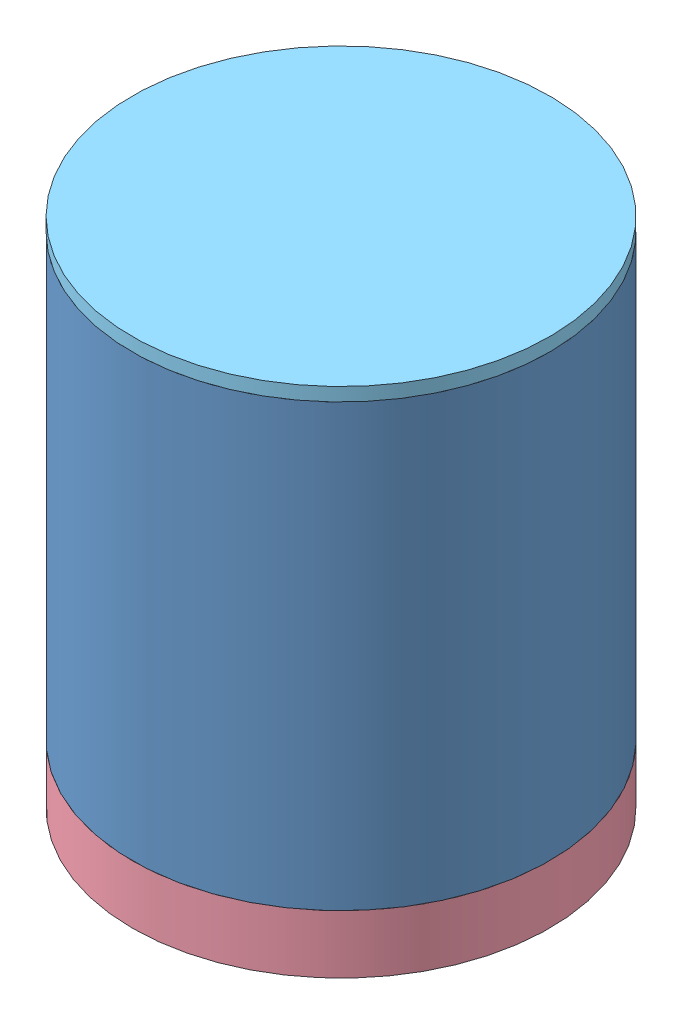
SolidWorks assembly Flour Dis. MEchanism_1.4, configuration Default. Lengths in mm.
Overall size (170.44 160 170.44).
5 component instances, 5 part files, 12 mates.
Components (placement in the parent):
- Flour container_ top part-1: Flour container_ top part [Default] at origin size (125 140 125)
- Flour Dis. MEchanism-2: Flour Dis. MEchanism [Default] at (0 -6 0) x (0.999465 0 -0.032695) z (0.032695 0 0.999465) size (118 10 118)
- Flour tracker-2: Flour tracker [Default] at (0 -16 0) x (-0.174382 0 0.984678) z (-0.984678 0 -0.174382) size (114 35 30)
- Flour container-3: Flour container [Default] at (0 -9.5 0) x (-1 0 0) z (0 0 -1) size (125 17.5 125)
- F CAP-1: F CAP [Default] at (0 140 0) x (0.494047 0 0.869435) z (-0.869435 0 0.494047) size (125 7 125)
Mates (geometry in assembly coordinates):
- Concentric3: concentric anti-aligned: cylinder of Flour container_ top part-1 through (0 0 0) axis (0 -1 0) radius 15; cylinder of Flour Dis. MEchanism-2 through (0 -10 0) axis (0 1 0) radius 10
- Coincident2: coincident anti-aligned: plane of Flour container_ top part-1 through (60.5 0 0) normal (0 -1 0); plane of Flour Dis. MEchanism-2 through (0 0 0) normal (0 1 0)
- Coincident4: coincident anti-aligned: plane of Flour Dis. MEchanism-2 through (0 4 0) normal (0 1 0); plane of Flour tracker-2 through (-2.6157 4 14.7702) normal (0 -1 0)
- Concentric5: concentric anti-aligned: cylinder of Flour Dis. MEchanism-2 through (0 -10 0) axis (0 1 0) radius 10; cylinder of Flour tracker-2 through (0 -16 0) axis (0 -1 0) radius 15
- Coincident5: coincident aligned: plane of Flour container_ top part-1 through (0 0 0) normal (0 0 1)
- Coincident6: coincident aligned: plane of Flour container_ top part-1 through (0 0 0) normal (0 1 0)
- Coincident7: coincident aligned: plane of Flour container_ top part-1 through (0 0 0) normal (1 0 0)
- Concentric6: concentric: cylinder of Flour container_ top part-1 through (0 0 0) axis (0 -1 0) radius 62.5; cylinder of Flour container-3 through (0 -9.5 0) axis (0 -1 0) radius 62.5
- Coincident8: coincident: plane of Flour container_ top part-1 through (60.5 8 0) normal (0 -1 0); plane of Flour container-3 through (-62.5 8 0) normal (0 1 0)
- Width2: width anti-aligned: plane of Flour container-3 through (0 8 0) normal (-0.965926 0 -0.258819); plane of Flour container_ top part-1 through (0 8 0) normal (0.965926 0 -0.258819); plane of Flour container-3 through (0 -6 0) normal (0.92388 0 0.382683); plane of Flour container_ top part-1 through (0 -6 0) normal (-0.92388 0 0.382683)
- Concentric7: concentric: cylinder of Flour container_ top part-1 through (0 0 0) axis (0 -1 0) radius 62.5; cylinder of F CAP-1 through (0 169.4056 0) axis (0 -1 0) radius 62.5
- Coincident9: coincident anti-aligned: plane of Flour container_ top part-1 through (62.5 140 0) normal (0 1 0); plane of F CAP-1 through (-30.8779 140 -54.3397) normal (0 -1 0)
